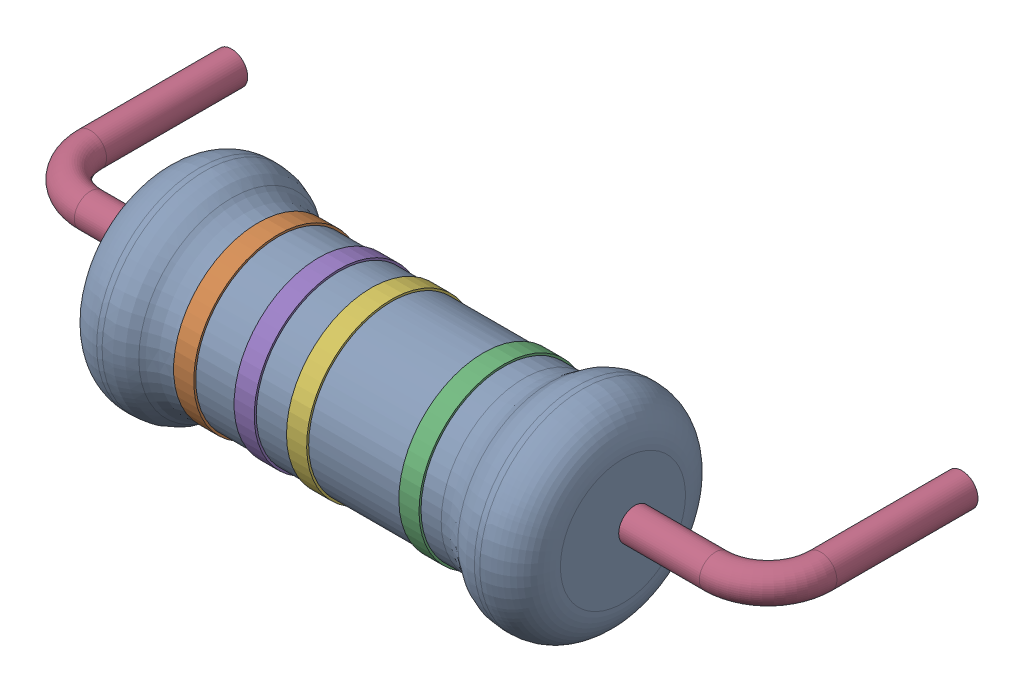
SolidWorks assembly R51.step, configuration Default. Lengths in mm.
Overall size (18.91 5.72 7.96).
7 component instances, 6 part files, 0 mates.
Components (placement in the parent):
- Res_Yageo_KNP100JR-73-22R_eec.step-1: Res_Yageo_KNP100JR-73-22R_eec.step [Default] at (52.832 61.976 0) x (1 0 0) z (0 0 1) size (18.91 5.72 7.96)
  - 1.step-1: 1.step [Default] at (0 0 2.55) size (11.5 5.1 5.1)
  - 2.step-1: 2.step [Default] at (-3.2931 0 2.55) x (0 0 -1) z (1 0 0) size (4.2 4.2 0.5)
  - 3.step-1: 3.step [Default] at (2.7931 0 2.55) x (0 -0.492137 0.870518) z (-1 0 0) size (4.2 4.2 0.5)
  - 4.step-1: 4.step [Default] at (0 0 -2.55) size (18.91 0.8 5.21)
  - 5.step-1: 5.step [Default] at (-1.7931 0 2.55) x (0 0 -1) z (1 0 0) size (4.2 4.2 0.5)
  - 6.step-1: 6.step [Default] at (0.0069 0 2.55) x (0 -0.017206 0.999852) z (-1 0 0) size (4.2 4.2 0.5)
